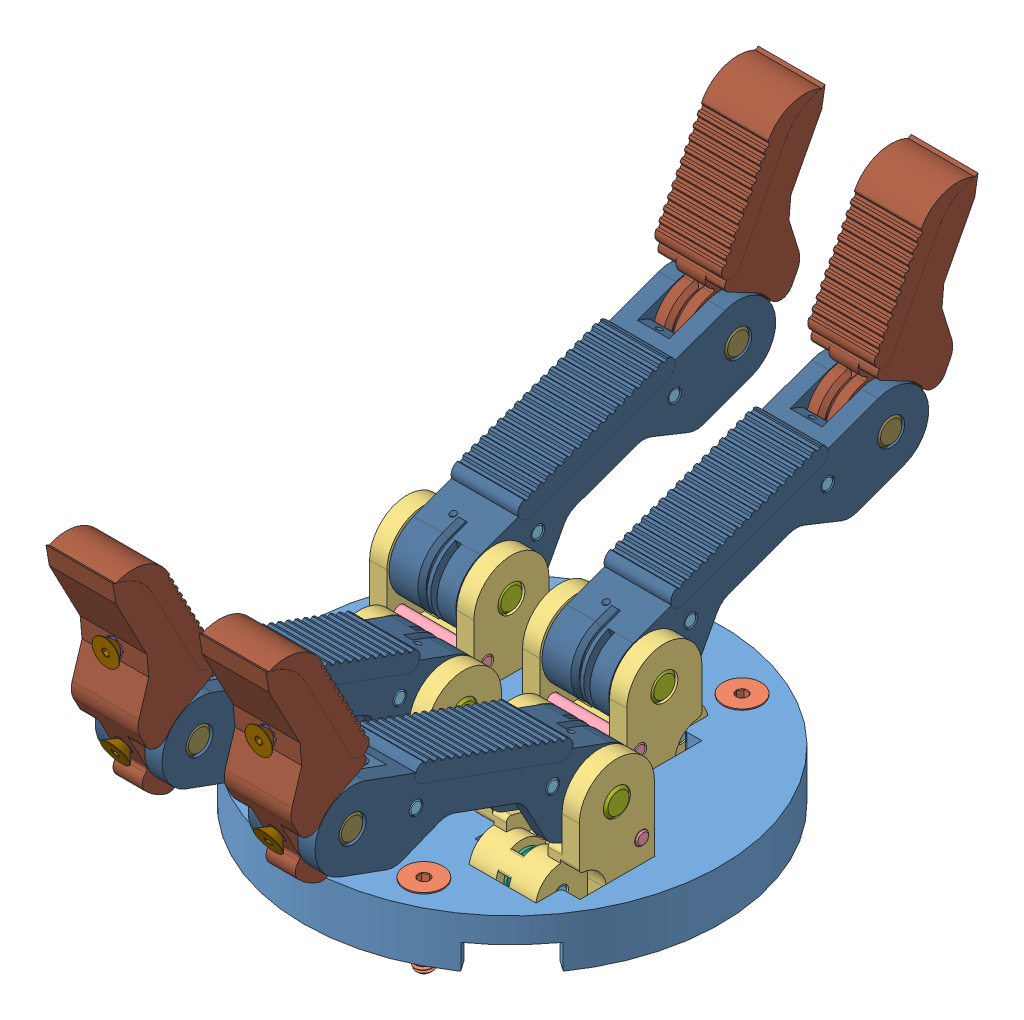
SolidWorks assembly block_top_pp_t, configuration Default. Lengths in mm.
Overall size (100 103.89 212.12).
73 component instances, 12 part files, 20 mates.
Components (placement in the parent):
- a1_p_t-1: a1_p_t [Default] at origin size (100 12 100)
- 92210A197 8-32 L3-4 countersunk-1: 92210A197 8-32 L3-4 countersunk [92210A197] at (17.0093 1.7845 38.128) x (0.445326 0 -0.895368) z (0 1 0) size (9.12 9.12 19.5)
- 92210A197 8-32 L3-4 countersunk-2: 92210A197 8-32 L3-4 countersunk [92210A197] at (-17.0093 1.7845 38.128) x (1 0 0) z (0 1 0) size (9.12 9.12 19.5)
- 92210A197 8-32 L3-4 countersunk-3: 92210A197 8-32 L3-4 countersunk [92210A197] at (17.0093 1.7845 -38.128) x (0.865412 0 0.501062) z (0 1 0) size (9.12 9.12 19.5)
- 92210A197 8-32 L3-4 countersunk-4: 92210A197 8-32 L3-4 countersunk [92210A197] at (-17.0093 1.7845 -38.128) x (1 0 0) z (0 1 0) size (9.12 9.12 19.5)
- block_finger_pp_t-1: block_finger_pp_t [Default] at (-27.425 -4.5 0) size (25.4 90.81 104.27)
  - c1_t-1: c1_t [Default] at origin size (25 30.67 32)
  - 98381A475 D1-8 L1-1: 98381A475 D1-8 L1 [98381A475] at (-0.2 11.2575 -8.8732) size (25.4 3.17 3.17)
  - 98381A472 D1-8 L5-8-3: 98381A472 D1-8 L5-8 [98381A472] at (0.0625 4.925 -23.535) size (15.88 3.17 3.17)
  - 3434T31 - nylon pulley-1: 3434T31 - nylon pulley [Default] at (-0.15 4.925 -23.535) x (0 -1 0) z (0 0 1) size (9.5 2.4 9.5)
  - 98381A472 D1-8 L5-8-1: 98381A472 D1-8 L5-8 [98381A472] at (0.0875 27.8748 -25.4819) size (15.88 3.17 3.17)
  - 98381A472 D1-8 L5-8-2: 98381A472 D1-8 L5-8 [98381A472] at (0.0875 39.839 -58.2703) size (15.88 3.17 3.17)
  - 98381A542 D1-4 L1-1: 98381A542 D1-4 L1 [98381A542] at (-0.2 21.67 -14.7858) size (25.4 6.35 6.35)
  - 93365A120 4-40 insert-1: 93365A120 4-40 insert [93365A120] at (0 64.964 -86.0368) x (1 0 0) z (0 0.995964 -0.089757) size (4.37 3.82 4.37)
  - 91253A106 4-40 L1-4 countersunk-1: 91253A106 4-40 L1-4 countersunk [91253A106] at (0 64.7736 -88.1494) x (1 0 0) z (0 -0.089757 -0.995964) size (6.48 6.48 6.63)
  - finger_pp_t_A-1: finger_pp_t_A [Default] at (0.15 21.67 -14.7858) x (1 0 0) z (0 -0.342783 0.939415) size (16 20.25 80.5)
  - finger_pp_t_B-1: finger_pp_t_B [Default] at (0 43.0939 -73.4992) x (1 0 0) z (0 -0.885802 0.464064) size (16 22.88 57.08)
  - 98381A539 D1-4 L5-8-1: 98381A539 D1-4 L5-8 [98381A539] at (0.2125 43.0939 -73.4992) size (15.88 6.35 6.35)
  - 93365A120 4-40 insert-2: 93365A120 4-40 insert [93365A120] at (0 43.6982 -83.9761) x (1 0 0) z (0 0.885802 -0.464064) size (4.37 3.82 4.37)
  - 93365A120 4-40 insert-3: 93365A120 4-40 insert [93365A120] at (0.15 30.6972 -65.7809) x (-0.837169 0.187483 -0.513807) z (-0.546944 -0.286967 0.786449) size (4.37 3.82 4.37)
  - 91253A106 4-40 L1-4 countersunk-2: 91253A106 4-40 L1-4 countersunk [91253A106] at (0 42.7139 -85.855) x (1 0 0) z (0 -0.464064 -0.885802) size (6.48 6.48 6.63)
  - 91253A106 4-40 L1-4 countersunk-3: 91253A106 4-40 L1-4 countersunk [91253A106] at (0.15 28.7045 -66.5081) x (1 0 0) z (0 -0.939415 -0.342783) size (6.48 6.48 6.63)
- block_finger_pp_t-2: block_finger_pp_t [Default] at (9.2417 -4.5 0) size (25.4 90.81 104.27)
  - c1_t-1: c1_t [Default] at origin size (25 30.67 32)
  - 98381A475 D1-8 L1-1: 98381A475 D1-8 L1 [98381A475] at (-0.2 11.2575 -8.8732) size (25.4 3.17 3.17)
  - 98381A472 D1-8 L5-8-3: 98381A472 D1-8 L5-8 [98381A472] at (0.0625 4.925 -23.535) size (15.88 3.17 3.17)
  - 3434T31 - nylon pulley-1: 3434T31 - nylon pulley [Default] at (-0.15 4.925 -23.535) x (0 -1 0) z (0 0 1) size (9.5 2.4 9.5)
  - 98381A472 D1-8 L5-8-1: 98381A472 D1-8 L5-8 [98381A472] at (0.0875 27.8748 -25.4819) size (15.88 3.17 3.17)
  - 98381A472 D1-8 L5-8-2: 98381A472 D1-8 L5-8 [98381A472] at (0.0875 39.839 -58.2703) size (15.88 3.17 3.17)
  - 98381A542 D1-4 L1-1: 98381A542 D1-4 L1 [98381A542] at (-0.2 21.67 -14.7858) size (25.4 6.35 6.35)
  - 93365A120 4-40 insert-1: 93365A120 4-40 insert [93365A120] at (0 64.964 -86.0368) x (1 0 0) z (0 0.995964 -0.089757) size (4.37 3.82 4.37)
  - 91253A106 4-40 L1-4 countersunk-1: 91253A106 4-40 L1-4 countersunk [91253A106] at (0 64.7736 -88.1494) x (1 0 0) z (0 -0.089757 -0.995964) size (6.48 6.48 6.63)
  - finger_pp_t_A-1: finger_pp_t_A [Default] at (0.15 21.67 -14.7858) x (1 0 0) z (0 -0.342783 0.939415) size (16 20.25 80.5)
  - finger_pp_t_B-1: finger_pp_t_B [Default] at (0 43.0939 -73.4992) x (1 0 0) z (0 -0.885802 0.464064) size (16 22.88 57.08)
  - 98381A539 D1-4 L5-8-1: 98381A539 D1-4 L5-8 [98381A539] at (0.2125 43.0939 -73.4992) size (15.88 6.35 6.35)
  - 93365A120 4-40 insert-2: 93365A120 4-40 insert [93365A120] at (0 43.6982 -83.9761) x (1 0 0) z (0 0.885802 -0.464064) size (4.37 3.82 4.37)
  - 93365A120 4-40 insert-3: 93365A120 4-40 insert [93365A120] at (0.15 30.6972 -65.7809) x (-0.837169 0.187483 -0.513807) z (-0.546944 -0.286967 0.786449) size (4.37 3.82 4.37)
  - 91253A106 4-40 L1-4 countersunk-2: 91253A106 4-40 L1-4 countersunk [91253A106] at (0 42.7139 -85.855) x (1 0 0) z (0 -0.464064 -0.885802) size (6.48 6.48 6.63)
  - 91253A106 4-40 L1-4 countersunk-3: 91253A106 4-40 L1-4 countersunk [91253A106] at (0.15 28.7045 -66.5081) x (1 0 0) z (0 -0.939415 -0.342783) size (6.48 6.48 6.63)
- block_finger_pp_t-3: block_finger_pp_t [Default] at (-9.2417 -4.5 0) x (-1 0 0) z (0 0 -1) size (25.4 90.81 104.27)
  - c1_t-1: c1_t [Default] at origin size (25 30.67 32)
  - 98381A475 D1-8 L1-1: 98381A475 D1-8 L1 [98381A475] at (-0.2 11.2575 -8.8732) size (25.4 3.17 3.17)
  - 98381A472 D1-8 L5-8-3: 98381A472 D1-8 L5-8 [98381A472] at (0.0625 4.925 -23.535) size (15.88 3.17 3.17)
  - 3434T31 - nylon pulley-1: 3434T31 - nylon pulley [Default] at (-0.15 4.925 -23.535) x (0 -1 0) z (0 0 1) size (9.5 2.4 9.5)
  - 98381A472 D1-8 L5-8-1: 98381A472 D1-8 L5-8 [98381A472] at (0.0875 27.8748 -25.4819) size (15.88 3.17 3.17)
  - 98381A472 D1-8 L5-8-2: 98381A472 D1-8 L5-8 [98381A472] at (0.0875 39.839 -58.2703) size (15.88 3.17 3.17)
  - 98381A542 D1-4 L1-1: 98381A542 D1-4 L1 [98381A542] at (-0.2 21.67 -14.7858) size (25.4 6.35 6.35)
  - 93365A120 4-40 insert-1: 93365A120 4-40 insert [93365A120] at (0 64.964 -86.0368) x (1 0 0) z (0 0.995964 -0.089757) size (4.37 3.82 4.37)
  - 91253A106 4-40 L1-4 countersunk-1: 91253A106 4-40 L1-4 countersunk [91253A106] at (0 64.7736 -88.1494) x (1 0 0) z (0 -0.089757 -0.995964) size (6.48 6.48 6.63)
  - finger_pp_t_A-1: finger_pp_t_A [Default] at (0.15 21.67 -14.7858) x (1 0 0) z (0 -0.342783 0.939415) size (16 20.25 80.5)
  - finger_pp_t_B-1: finger_pp_t_B [Default] at (0 43.0939 -73.4992) x (1 0 0) z (0 -0.885802 0.464064) size (16 22.88 57.08)
  - 98381A539 D1-4 L5-8-1: 98381A539 D1-4 L5-8 [98381A539] at (0.2125 43.0939 -73.4992) size (15.88 6.35 6.35)
  - 93365A120 4-40 insert-2: 93365A120 4-40 insert [93365A120] at (0 43.6982 -83.9761) x (1 0 0) z (0 0.885802 -0.464064) size (4.37 3.82 4.37)
  - 93365A120 4-40 insert-3: 93365A120 4-40 insert [93365A120] at (0.15 30.6972 -65.7809) x (-0.837169 0.187483 -0.513807) z (-0.546944 -0.286967 0.786449) size (4.37 3.82 4.37)
  - 91253A106 4-40 L1-4 countersunk-2: 91253A106 4-40 L1-4 countersunk [91253A106] at (0 42.7139 -85.855) x (1 0 0) z (0 -0.464064 -0.885802) size (6.48 6.48 6.63)
  - 91253A106 4-40 L1-4 countersunk-3: 91253A106 4-40 L1-4 countersunk [91253A106] at (0.15 28.7045 -66.5081) x (1 0 0) z (0 -0.939415 -0.342783) size (6.48 6.48 6.63)
- block_finger_pp_t-4: block_finger_pp_t [Default] at (27.425 -4.5 0) x (-1 0 0) z (0 0 -1) size (25.4 90.81 104.27)
  - c1_t-1: c1_t [Default] at origin size (25 30.67 32)
  - 98381A475 D1-8 L1-1: 98381A475 D1-8 L1 [98381A475] at (-0.2 11.2575 -8.8732) size (25.4 3.17 3.17)
  - 98381A472 D1-8 L5-8-3: 98381A472 D1-8 L5-8 [98381A472] at (0.0625 4.925 -23.535) size (15.88 3.17 3.17)
  - 3434T31 - nylon pulley-1: 3434T31 - nylon pulley [Default] at (-0.15 4.925 -23.535) x (0 -1 0) z (0 0 1) size (9.5 2.4 9.5)
  - 98381A472 D1-8 L5-8-1: 98381A472 D1-8 L5-8 [98381A472] at (0.0875 27.8748 -25.4819) size (15.88 3.17 3.17)
  - 98381A472 D1-8 L5-8-2: 98381A472 D1-8 L5-8 [98381A472] at (0.0875 39.839 -58.2703) size (15.88 3.17 3.17)
  - 98381A542 D1-4 L1-1: 98381A542 D1-4 L1 [98381A542] at (-0.2 21.67 -14.7858) size (25.4 6.35 6.35)
  - 93365A120 4-40 insert-1: 93365A120 4-40 insert [93365A120] at (0 64.964 -86.0368) x (1 0 0) z (0 0.995964 -0.089757) size (4.37 3.82 4.37)
  - 91253A106 4-40 L1-4 countersunk-1: 91253A106 4-40 L1-4 countersunk [91253A106] at (0 64.7736 -88.1494) x (1 0 0) z (0 -0.089757 -0.995964) size (6.48 6.48 6.63)
  - finger_pp_t_A-1: finger_pp_t_A [Default] at (0.15 21.67 -14.7858) x (1 0 0) z (0 -0.342783 0.939415) size (16 20.25 80.5)
  - finger_pp_t_B-1: finger_pp_t_B [Default] at (0 43.0939 -73.4992) x (1 0 0) z (0 -0.885802 0.464064) size (16 22.88 57.08)
  - 98381A539 D1-4 L5-8-1: 98381A539 D1-4 L5-8 [98381A539] at (0.2125 43.0939 -73.4992) size (15.88 6.35 6.35)
  - 93365A120 4-40 insert-2: 93365A120 4-40 insert [93365A120] at (0 43.6982 -83.9761) x (1 0 0) z (0 0.885802 -0.464064) size (4.37 3.82 4.37)
  - 93365A120 4-40 insert-3: 93365A120 4-40 insert [93365A120] at (0.15 30.6972 -65.7809) x (-0.837169 0.187483 -0.513807) z (-0.546944 -0.286967 0.786449) size (4.37 3.82 4.37)
  - 91253A106 4-40 L1-4 countersunk-2: 91253A106 4-40 L1-4 countersunk [91253A106] at (0 42.7139 -85.855) x (1 0 0) z (0 -0.464064 -0.885802) size (6.48 6.48 6.63)
  - 91253A106 4-40 L1-4 countersunk-3: 91253A106 4-40 L1-4 countersunk [91253A106] at (0.15 28.7045 -66.5081) x (1 0 0) z (0 -0.939415 -0.342783) size (6.48 6.48 6.63)
Mates (geometry in assembly coordinates):
- Concentric1: concentric aligned: cylinder of a1_p_t-1 through (17.0093 1.5 38.128) axis (0 1 0) radius 2.4574; circle of 92210A197 8-32 L3-4 countersunk-1
- Coincident13: coincident aligned: cone of a1_p_t-1 through (17.0093 1.5 38.128) axis (0 -1 0); cone of 92210A197 8-32 L3-4 countersunk-1 through (17.0093 -1.0603 38.128) axis (0 -1 0)
- Concentric3: concentric aligned: cylinder of a1_p_t-1 through (17.0093 1.5 -38.128) axis (0 1 0) radius 2.4574; circle of 92210A197 8-32 L3-4 countersunk-3
- Coincident14: coincident aligned: cone of a1_p_t-1 through (17.0093 1.5 -38.128) axis (0 -1 0); cone of 92210A197 8-32 L3-4 countersunk-3 through (17.0093 -1.0603 -38.128) axis (0 -1 0)
- Concentric5: concentric aligned: cylinder of a1_p_t-1 through (-17.0093 1.5 -38.128) axis (0 1 0) radius 2.4574; circle of 92210A197 8-32 L3-4 countersunk-4
- Coincident15: coincident aligned: cone of a1_p_t-1 through (-17.0093 1.5 -38.128) axis (0 -1 0); cone of 92210A197 8-32 L3-4 countersunk-4 through (-17.0093 -1.0603 -38.128) axis (0 -1 0)
- Concentric7: concentric aligned: cylinder of a1_p_t-1 through (-17.0093 1.5 38.128) axis (0 1 0) radius 2.4574; circle of 92210A197 8-32 L3-4 countersunk-2
- Coincident16: coincident aligned: cone of a1_p_t-1 through (-17.0093 1.5 38.128) axis (0 -1 0); cone of 92210A197 8-32 L3-4 countersunk-2 through (-17.0093 -1.0603 38.128) axis (0 -1 0)
- Coincident17: coincident anti-aligned: plane of a1_p_t-1 through (-14.925 1.5 -5.7858) normal (-1 0 0); plane of block_finger_pp_t-1/c1_t-1 through (-14.925 17.17 -14.7858) normal (1 0 0)
- Coincident18: coincident anti-aligned: plane of a1_p_t-1 through (-40.075 1.5 -5.7858) normal (0 0 -1); plane of block_finger_pp_t-1/c1_t-1 through (-39.925 17.17 -5.7858) normal (0 0 1)
- Coincident19: coincident anti-aligned: plane of a1_p_t-1 through (0 -1.5 0) normal (0 -1 0); plane of block_finger_pp_t-1/c1_t-1 through (-39.925 -1.5 -5.7858) normal (0 1 0)
- Coincident20: coincident anti-aligned: plane of a1_p_t-1 through (21.7417 1.5 -5.7858) normal (-1 0 0); plane of block_finger_pp_t-2/c1_t-1 through (21.7417 17.17 -14.7858) normal (1 0 0)
- Coincident21: coincident anti-aligned: plane of a1_p_t-1 through (-3.4083 1.5 -5.7858) normal (0 0 -1); plane of block_finger_pp_t-2/c1_t-1 through (-3.2583 17.17 -5.7858) normal (0 0 1)
- Coincident22: coincident anti-aligned: plane of a1_p_t-1 through (0 -1.5 0) normal (0 -1 0); plane of block_finger_pp_t-2/c1_t-1 through (-3.2583 -1.5 -5.7858) normal (0 1 0)
- Coincident23: coincident anti-aligned: plane of a1_p_t-1 through (14.925 1.5 5.7858) normal (1 0 0); plane of block_finger_pp_t-4/c1_t-1 through (14.925 17.17 14.7858) normal (-1 0 0)
- Coincident24: coincident anti-aligned: plane of a1_p_t-1 through (40.075 1.5 5.7858) normal (0 0 1); plane of block_finger_pp_t-4/c1_t-1 through (39.925 17.17 5.7858) normal (0 0 -1)
- Coincident25: coincident anti-aligned: plane of a1_p_t-1 through (0 -1.5 0) normal (0 -1 0); plane of block_finger_pp_t-4/c1_t-1 through (39.925 -1.5 5.7858) normal (0 1 0)
- Coincident26: coincident anti-aligned: plane of a1_p_t-1 through (-21.7417 1.5 23.7858) normal (1 0 0); plane of block_finger_pp_t-3/c1_t-1 through (-21.7417 17.17 14.7858) normal (-1 0 0)
- Coincident27: coincident anti-aligned: plane of a1_p_t-1 through (-21.7417 1.5 5.7858) normal (0 0 1); plane of block_finger_pp_t-3/c1_t-1 through (3.2583 17.17 5.7858) normal (0 0 -1)
- Coincident28: coincident anti-aligned: plane of a1_p_t-1 through (0 -1.5 0) normal (0 -1 0); plane of block_finger_pp_t-3/c1_t-1 through (3.2583 -1.5 5.7858) normal (0 1 0)
